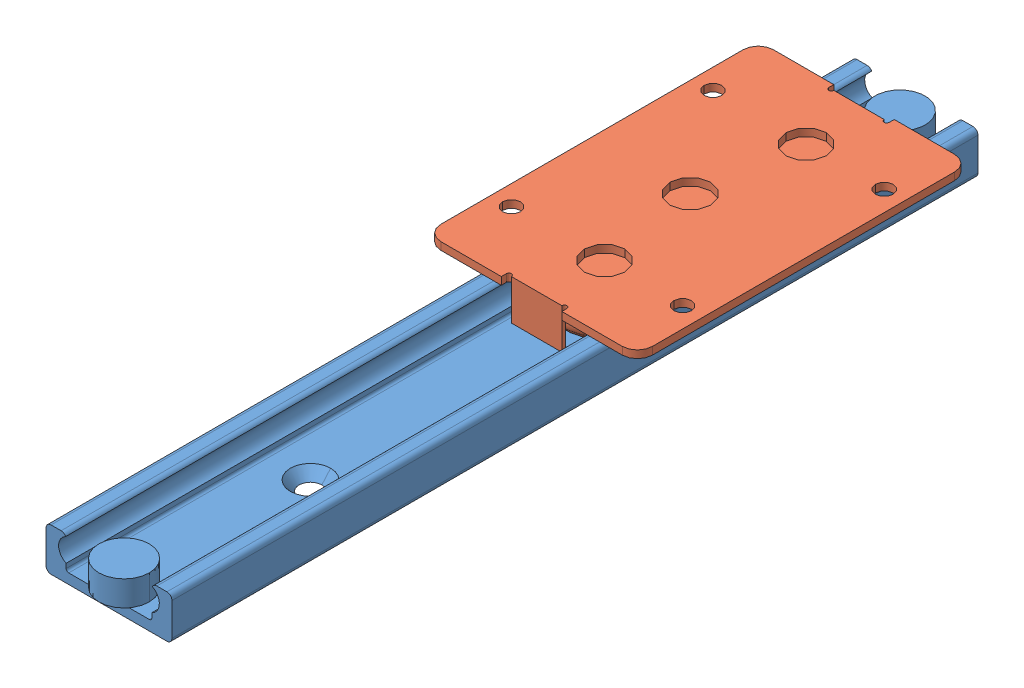
SolidWorks assembly RSR25_160, configuration Default. Lengths in mm.
Overall size (42 12 164).
2 component instances, 2 part files, 3 mates.
Components (placement in the parent):
- _RSRR25_160_2-1: _RSRR25_160_2 [Default] at origin size (25 8.5 164)
- _RSRS25_4-1: _RSRS25_4 [Default] at (0 3.2 10.1152) x (-1 0 0) z (0 0 -1) size (42 8.8 66)
Mates (geometry in assembly coordinates):
- Tangente2: tangent: cylinder of _RSRR25_160_2-1 through (7.5 5.7 160) axis (0 0 1) radius 2.5; torus of _RSRS25_4-1
- Parallelo1: parallel: plane of _RSRR25_160_2-1 through (-12.5 7.5 160) normal (-1 0 0); plane of _RSRS25_4-1 through (-21 10.5 13.1152) normal (-1 0 0)
- Parallelo2: parallel: plane of _RSRR25_160_2-1 through (-9.5 8.5 160) normal (0 1 0); plane of _RSRS25_4-1 through (18 12 13.1152) normal (0 1 0)
